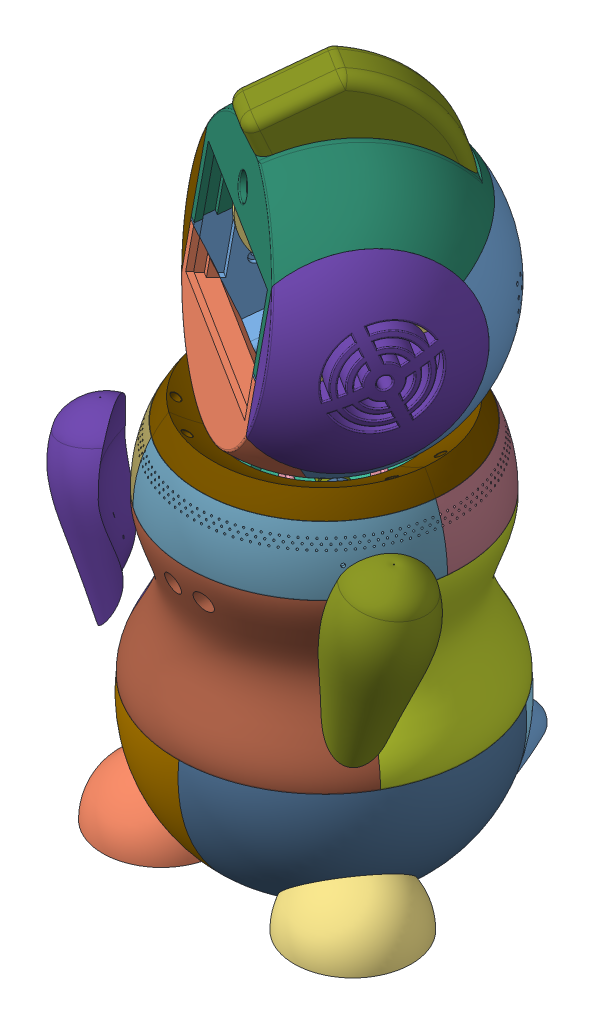
SolidWorks assembly finalAssembly, configuration Défaut. Lengths in mm.
Overall size (453.55 762.15 522.29).
107 component instances, 77 part files, 19 mates.
Components (placement in the parent):
- neck-1: neck [Défaut] at (0 47.0722 0) x (1 0 0) z (0 -1 0) size (276.15 243.78 413.67)
  - actuator_interface_3-1: actuator_interface_3 [Défaut] at (0 0 -18) x (0.532073 -0.846698 0) z (0 0 -1) size (99.5 102 78)
  - actuator_interface_2-1: actuator_interface_2 [Défaut] at (0 0 -93.996) x (0.846698 0.532073 0) z (-0.532073 0.846698 0) size (35 70 102)
  - actuator_interface_4-1: actuator_interface_4 [Défaut] at (0 0 -18) x (-0.532073 0.846698 0) z (0 0 -1) size (99.5 102 78)
  - actuator_interface_1-1: actuator_interface_1 [Défaut] at (0 0 -114) x (-0.846698 -0.532073 0) z (0.532073 -0.846698 0) size (80 70 102)
  - AX-18A-1: AX-18A [Défaut] at (45.7217 28.732 -112.0076) x (-0.532073 0.846698 0) z (-0.846698 -0.532073 0) size (32 50.04 40.32)
    - ASSY_DUMMY___^AX-18A-1: ASSY_DUMMY___^AX-18A [Défaut] at origin size (32 50.04 38.37) (virtual)
    - ASSY_GEAR-WHEEL___DUMMY^AX-18A-1: ASSY_GEAR-WHEEL___DUMMY^AX-18A [Défaut] at (0 0 -2) x (-1 0 0) z (0 0 1) size (6.5 6.5 5.51) (virtual)
    - DX124_SCREW-COVER___^AX-18A-1: DX124_SCREW-COVER___^AX-18A [Défaut] at (9.5 8.5 14.5) x (-1 0 0) z (0 1 0) size (3.5 30.7 3.5) (virtual)
    - DX124_SCREW-COVER___^AX-18A-2: DX124_SCREW-COVER___^AX-18A [Défaut] at (-9.5 8.5 14.5) x (-1 0 0) z (0 1 0) size (3.5 30.7 3.5) (virtual)
    - DX124_SCREW-COVER___^AX-18A-3: DX124_SCREW-COVER___^AX-18A [Défaut] at (10.5 -33 14.5) x (-1 0 0) z (0 1 0) size (3.5 30.7 3.5) (virtual)
    - DX124_SCREW-COVER___^AX-18A-4: DX124_SCREW-COVER___^AX-18A [Défaut] at (-10.5 -33 14.5) x (-1 0 0) z (0 1 0) size (3.5 30.7 3.5) (virtual)
    - 099990987____^AX-18A-1: 099990987____^AX-18A [Défaut] at (5.05 -15.19 -9.75) x (1 0 0) z (0 1 0) size (9.9 9.43 4.9) (virtual)
    - 099990987____^AX-18A-2: 099990987____^AX-18A [Défaut] at (-4.95 -15.19 -9.75) x (1 0 0) z (0 1 0) size (9.9 9.43 4.9) (virtual)
    - DC04_B01_INSERT_M3^AX-18A-1: DC04_B01_INSERT_M3^AX-18A [Défaut] at (0 0 -18.4) x (-1 0 0) z (0 1 0) size (4.98 7 4.98) (virtual)
    - DC04_B01_HORN2_DUMMY^AX-18A-1: DC04_B01_HORN2_DUMMY^AX-18A [Défaut] at (0 0 19.1) x (0 1 0) z (0 0 1) size (22 22 6.7) (virtual)
    - BHS_M2_6X8^AX-18A-1: BHS_M2_6X8^AX-18A [Défaut] at (0 0 19.55) x (0 1 0) z (1 0 0) size (5.5 9.6 5.5) (virtual)
  - neck_axis-1: neck_axis [Défaut] at (-35.8296 0.6331 -91.786) x (0.491491 -0.782119 0.383049) z (0.846698 0.532073 0) size (5 5 105) (hidden)
  - neck_axis-2: neck_axis [Défaut] at (-14.9723 -32.5575 -91.786) x (0.491491 -0.782119 0.383049) z (0.846698 0.532073 0) size (5 5 105)
  - ballBearing-1: ballBearing [Défaut] at (10.4286 -16.5953 -91.786) x (-0.846698 -0.532073 0) z (-0.371739 0.591555 0.715453) size (3.01 11 11)
    - ball1-1: ball1 [Défaut] at (1.5 3.0642 2.5712) size (1.96 2.07 2.07)
    - ball2-1: ball2 [Défaut] at (1.5 0.6946 3.9392) size (2.15 2.2 2.14)
    - ball3-1: ball3 [Défaut] at (1.5 -2 3.4641) size (1.97 2.11 2.11)
    - ball4-1: ball4 [Défaut] at (1.5 -3.7588 1.3681) size (2.08 2.02 2.1)
    - ball5-1: ball5 [Défaut] at (1.5 -3.7588 -1.3681) size (1.97 2.13 2.17)
    - ball6-1: ball6 [Défaut] at (1.5 -2 -3.4641) size (2.07 2.2 2.04)
    - ball7-1: ball7 [Défaut] at (1.5 0.6946 -3.9392) size (2.09 2.05 2.22)
    - ball8-1: ball8 [Défaut] at (1.5 3.0642 -2.5712) size (2.02 2.17 2.18)
    - ball9-1: ball9 [Défaut] at (1.5 4 0) size (2.21 2.22 2.24)
    - external_ring-1: external_ring [Défaut] at (1.5 0 0) size (3.01 11 11)
    - internal_ring-1: internal_ring [Défaut] at (1.5 0 0) size (3.01 6.8 6.8)
  - ballBearing-2: ballBearing [Défaut] at (-10.4286 16.5953 -91.786) x (-0.846698 -0.532073 0) z (-0.363526 0.578486 -0.730208) size (3.01 11 11)
    - ball1-1: ball1 [Défaut] at (1.5 3.0642 2.5712) size (1.96 2.07 2.07)
    - ball2-1: ball2 [Défaut] at (1.5 0.6946 3.9392) size (2.15 2.2 2.14)
    - ball3-1: ball3 [Défaut] at (1.5 -2 3.4641) size (1.97 2.11 2.11)
    - ball4-1: ball4 [Défaut] at (1.5 -3.7588 1.3681) size (2.08 2.02 2.1)
    - ball5-1: ball5 [Défaut] at (1.5 -3.7588 -1.3681) size (1.97 2.13 2.17)
    - ball6-1: ball6 [Défaut] at (1.5 -2 -3.4641) size (2.07 2.2 2.04)
    - ball7-1: ball7 [Défaut] at (1.5 0.6946 -3.9392) size (2.09 2.05 2.22)
    - ball8-1: ball8 [Défaut] at (1.5 3.0642 -2.5712) size (2.02 2.17 2.18)
    - ball9-1: ball9 [Défaut] at (1.5 4 0) size (2.21 2.22 2.24)
    - external_ring-1: external_ring [Défaut] at (1.5 0 0) size (3.01 11 11)
    - internal_ring-1: internal_ring [Défaut] at (1.5 0 0) size (3.01 6.8 6.8)
  - rack_pinion-1: rack_pinion [Défaut] at (-0.0372 0.0592 -246.5526) x (0.53176 -0.8462 -0.034291) z (0.846698 0.532073 0) size (127.33 287 240)
  - sprocket_2-1: sprocket_2 [Défaut] x (0.532073 -0.846698 0) z (0 0 -1) size (22 22 10)
  - sprocket_1-1: sprocket_1 [Défaut] at (0 0 -15) x (-0.532073 0.846698 0) z (0 0 1) size (22 22 10)
  - DYNAMIXEL AX-12A-1: DYNAMIXEL AX-12A [Défaut] at (0 0 -36) x (0.846698 0.532073 0) z (0 0 1) size (50 32 40.55)
    - AX-12A-01-1: AX-12A-01 [Défaut] at origin size (48.5 26 22)
    - AX-12A-02-1: AX-12A-02 [Défaut] at (0 0 13.5) size (50 32 8)
    - AX-12A-03-1: AX-12A-03 [Défaut] at (0 0 -13.5) x (1 0 0) z (0 0 -1) size (50 32 8)
    - AX-12A-04-1: AX-12A-04 [Défaut] at (0 0 21) size (22 22 6.7)
    - SetScrew-1: SetScrew [Défaut] at (33 10.4 14.5) x (0.31498 0.949098 0) z (0 0 -1) size (3.3 3.3 29.44)
    - SetScrew-2: SetScrew [Défaut] at (-9 9.25 14.5) x (0.31498 0.949098 0) z (0 0 -1) size (3.3 3.3 29.44)
    - SetScrew-3: SetScrew [Défaut] at (-9 -9.25 14.5) x (-0.958559 0.284893 0) z (0 0 -1) size (3.3 3.3 29.44)
    - SetScrew-4: SetScrew [Défaut] at (33 -10.4 14.5) x (0.31498 0.949098 0) z (0 0 -1) size (3.3 3.3 29.44)
    - M2.5 x 8-1: M2.5 x 8 [Défaut] at (0 0 21.6) x (0 0 -1) z (1 0 0) size (10.05 5 5)
  - actuator_holder-1: actuator_holder [Défaut] at origin size (120 120 45)
  - actuator_axis-1: actuator_axis [Défaut] at (27.9918 17.5903 -112.0076) x (-0.529316 0.84231 -0.10168) z (-0.846698 -0.532073 0) size (22 22 62.75)
  - ballBearing2-1: ballBearing2 [Défaut] at (-25.1385 -15.7973 -112.0076) x (0.846698 0.532073 0) z (0.023473 -0.037354 0.999026) size (5.01 19 19)
    - ball-1: ball [Défaut] at (2.5 6.0991 3.9196) size (3.2 3.01 3.02)
    - ball_2-1: ball_2 [Défaut] at (2.5 3.0118 6.5948) size (3.23 3.28 3.31)
    - ball_3-1: ball_3 [Défaut] at (2.5 -1.0318 7.1762) size (3.31 3.03 3.32)
    - ball_4-1: ball_4 [Défaut] at (2.5 -4.7477 5.4792) size (3.18 3.13 3.12)
    - ball_5-1: ball_5 [Défaut] at (2.5 -6.9563 2.0426) size (3.11 3.23 3.11)
    - ball_6-1: ball_6 [Défaut] at (2.5 -6.9563 -2.0426) size (3.2 3.24 3.25)
    - ball_7-1: ball_7 [Défaut] at (2.5 -4.7477 -5.4792) size (3.13 3.32 3.2)
    - ball_8-1: ball_8 [Défaut] at (2.5 -1.0318 -7.1762) size (3.23 3.19 3.29)
    - ball_9-1: ball_9 [Défaut] at (2.5 3.0118 -6.5948) size (3.19 2.92 2.97)
    - ball_10-1: ball_10 [Défaut] at (2.5 6.0991 -3.9196) size (3.19 2.92 2.97)
    - ball_11-1: ball_11 [Défaut] at (2.5 7.25 0) size (3.28 3.11 3.26)
    - external_bearing_ring-1: external_bearing_ring [Défaut] at (2.5 0 0) size (5 19 19)
    - internal_bearing_ring-1: internal_bearing_ring [Défaut] at (2.5 0 0) size (5.01 12.6 12.6)
  - actuator_interface_3_handle-1: actuator_interface_3_handle [Défaut] at (0 0 -93) x (-0.532073 0.846698 0) z (0 0 -1) size (51 102 7)
  - actuator_interface_4_handle-1: actuator_interface_4_handle [Défaut] at (0 0 -93) x (0.532073 -0.846698 0) z (0 0 1) size (121.83 102 7)
  - handle_microphone-1: handle_microphone [Défaut] at (-61.0037 21.8987 -111.996) x (0.846698 0.532073 0) z (-0.532073 0.846698 0) size (20.05 24.31 80)
- fullHead-2: fullHead [Défaut] at (-0.0372 293.6248 0.0592) x (0.493103 0.37566 -0.784684) z (0.846698 0 0.532073) size (324.69 440 242.7)
  - head_top-1: head_top [Défaut<Brut d'usinage>] at origin size (204.61 182.78 242.7)
  - antenna-1: antenna [Défaut] at (33.2003 132.5986 0) x (1 0.000018 0) z (0 0 1) size (117.93 116.64 43.21)
  - head_right-1: head_right [Défaut<Brut d'usinage>] at origin size (162.46 164.24 33.23)
  - head_left-1: head_left [Défaut<Brut d'usinage>] at origin size (162.65 164.24 32.5)
  - head_bottom_back-1: head_bottom_back [Défaut<Brut d'usinage>] at origin size (302.12 440 240)
  - head_bottom_front-1: head_bottom_front [Défaut<Brut d'usinage>] at origin size (78.16 121.67 175)
  - screen_ts-1: screen_ts [Défaut] at (-72.9065 -13.8984 83) x (0 0 -1) z (0.86143 -0.507877 0) size (164.9 100 7.6) (hidden)
  - speaker_holder-1: speaker_holder [Défaut] at (11.0602 1 -77.5) x (-1 -0.000004 0) z (0 0 -1) size (98 98 10)
  - speaker_holder-2: speaker_holder [Défaut] at (11.0602 1 77.5) x (1 0.000004 0) z (0 0 1) size (98 98 10)
  - logitech_webcam-1: logitech_webcam [Default] at (0.4902 95.7269 0) x (0 0 -1) z (-0.86143 0.507877 0) size (100.21 36.29 33.35) (hidden)
  - webcam_holder-1: webcam_holder [Défaut] at (10.2474 72.8969 0) x (0 0 1) z (-0.86143 0.507877 0) size (126 24 17.75)
- bodyAssembly-1: bodyAssembly [Défaut] at (-1.0427 -19.4867 -88.5189) x (0.011778 0 0.999931) z (-0.999931 0 0.011778) size (318.22 585.46 348.54)
  - body_bottom_back-3: body_bottom_back [Défaut] at (77.8148 3.5849 0.3337) x (0.049646 0 -0.998767) z (0.998767 0 0.049646) size (218.81 181.14 229.88)
  - hood_bottom-1: hood_bottom [Défaut] at (88.5251 -95.0219 0) x (-0.865075 0 0.501643) z (0.501643 0 0.865075) size (99.91 75.51 99.91)
  - body_middle_handle_left-1: body_middle_handle_left [Défaut] at (84.0876 21.8675 -7.018) x (0.889771 0 -0.456408) z (0.456408 0 0.889771) size (219.58 137 233.1)
  - body_middle_handle_right-1: body_middle_handle_right [Défaut] at (84.0879 21.8675 7.0182) x (0.88979 0 0.456369) z (-0.456369 0 0.88979) size (219.58 137 101.96)
  - body_bottom_left-1: body_bottom_left [Défaut] at (94.1692 3.5849 9.1085) x (-0.889781 0 0.456388) z (-0.456388 0 -0.889781) size (218.17 119.6 229.88)
  - body_bottom_right-1: body_bottom_right [Défaut] at (93.5912 3.5849 -9.4422) x (0.840134 0 0.542378) z (-0.542378 0 0.840134) size (218.17 119.6 229.88)
  - body_middle_front-1: body_middle_front [Défaut] at (96.8216 21.8675 -0.3339) x (-0.049625 0 0.998768) z (-0.998768 0 -0.049625) size (219.58 137 233.1)
  - body_top_left-1: body_top_left [Défaut] at (87.7005 20.6082 10.6911) x (-0.987582 0 -0.157104) z (0.157104 0 -0.987582) size (205.58 215.16 224.44)
  - body_top_middle-1: body_top_middle [Défaut] at (79.6784 20.6076 -6.0594) x (0.629847 0 -0.776719) z (0.776719 0 0.629847) size (205.58 215.16 224.44)
  - body_top_right-1: body_top_right [Défaut] at (98.196 20.6076 -4.6317) x (0.357735 0 0.933823) z (-0.933823 0 0.357735) size (205.58 215.16 224.44)
  - hood_top-1: hood_top [Défaut] at (88.5251 15.8089 0) x (0.889337 0 -0.457252) z (-0.457252 0 -0.889337) size (168.25 11.5 168.25)
  - right_arm-1: right_arm [Défaut] at (112.1996 28.4675 -37.1902) x (-0.23281 0 -0.972522) z (0.972522 0 -0.23281) size (99.49 162.31 86.07)
  - left_arm-1: left_arm [Défaut] at (107.8819 25.216 31.1666) x (0.235659 0 -0.971836) z (0.971836 0 0.235659) size (116.38 164.79 102.42)
  - body_top_hood-1: body_top_hood [Défaut] at (87.7413 20.6076 10.5995) x (-0.988027 0 -0.15428) z (0.15428 0 -0.988027) size (204.12 402.34 224.44)
  - body_top_hood-4: body_top_hood [Défaut] at (79.7375 20.6076 -5.9785) x (0.627624 0 -0.778517) z (0.778517 0 0.627624) size (204.12 402.34 224.44)
  - body_top_hood-5: body_top_hood [Défaut] at (98.0964 20.6076 -4.621) x (0.360404 0 0.932796) z (-0.932796 0 0.360404) size (204.12 402.34 224.44)
- tail-1: tail [Défaut] at (0 -11.0278 0.7241) size (129.75 64.88 157.15)
- left_foot-1: left_foot [Défaut] at (-0.3747 -11.0079 -0.08) x (0.977938 0 0.208895) z (-0.208895 0 0.977938) size (100 52.38 100)
- right_foot-1: right_foot [Défaut] at (-0.3747 -11.0079 0.08) x (0.977938 0 -0.208895) z (0.208895 0 0.977938) size (100 52.38 100)
Mates (geometry in assembly coordinates):
- Coïncidente114: coincident aligned: plane of left_foot-1 through (-81.6024 -117.5278 57.216) normal (0 -1 0); plane of right_foot-1 through (0 -117.5278 0) normal (0 -1 0)
- Coaxiale31: concentric: circle of ?; circle of tail-1
- Coïncidente131: coincident aligned: circle of ?; circle of right_foot-1
- Coïncidente137: coincident aligned: circle of bodyAssembly-1/body_bottom_back-3; circle of left_foot-1
- Distance20: distance = 60 mm: plane of assembly through (0 0 0) normal (0 0 1); point of left_foot-1
- Distance21: distance = 60 mm: point of right_foot-1; plane of assembly
- Coïncidente140: coincident aligned: plane of bodyAssembly-1/body_bottom_back-3 through (0 -117.5278 0) normal (0 -1 0); plane of tail-1 through (-41.08 -117.5278 -114.5551) normal (0 -1 0)
- Coïncidente143: coincident aligned: plane of tail-1 through (0 -11.0278 0.7241) normal (1 0 0); plane of assembly through (0 0 0) normal (1 0 0)
- Coïncidente144: coincident: circle of ?; point of tail-1
- Parallèle15: parallel anti-aligned: plane of ? through (0.8656 -57.4513 10.6879) normal (-1 0 0); plane of assembly through (0 0 0) normal (1 0 0)
- Distance22: distance = 0 mm aligned: plane of ? through (-0.0372 293.6248 0.0592) normal (0.846698 0 0.532073); plane of neck-1/actuator_interface_4-1
- Coïncidente149: coincident: plane of fullHead-2 through (-0.0372 244.5526 0.0592) normal (0.846698 0 0.532073); plane of neck-1/rack_pinion-1 through (-0.0372 244.5526 0.0592) normal (0.846698 0 0.532073)
- Tangent5: tangent aligned: cylinder of neck-1/rack_pinion-1 through (8.4298 293.6248 5.3799) axis (-0.846698 0 -0.532073) radius 120; sphere of fullHead-2/head_bottom_back-1
- Coïncidente151: coincident anti-aligned: line of neck-1/rack_pinion-1 through (-13.342 187.2215 40.0257) axis (-0.846698 0 -0.532073); line of fullHead-2/head_bottom_front-1 through (-30.2759 187.2215 29.3842) axis (0.846698 0 0.532073)
- Coïncidente152: coincident aligned: plane of neck-1/actuator_holder-1 through (0 47.0722 0) normal (0 0 1); plane of assembly through (0 0 0) normal (0 0 1)
- Coïncidente153: coincident aligned: plane of neck-1/actuator_holder-1; plane of assembly through (0 0 0) normal (1 0 0)
- Coïncidente155: coincident anti-aligned: plane of neck-1/actuator_holder-1 through (0 2.0722 0) normal (0 -1 0); plane of bodyAssembly-1/hood_top-1 through (0 2.0722 0) normal (0 1 0)
- Coaxiale32: concentric anti-aligned: circle of neck-1/actuator_holder-1; circle of bodyAssembly-1/body_middle_handle_right-1
- Coïncidente156: coincident anti-aligned: plane of neck-1/actuator_holder-1 through (0 2.0722 0) normal (0 -1 0); plane of bodyAssembly-1/hood_top-1 through (0 2.0722 0) normal (0 1 0)
